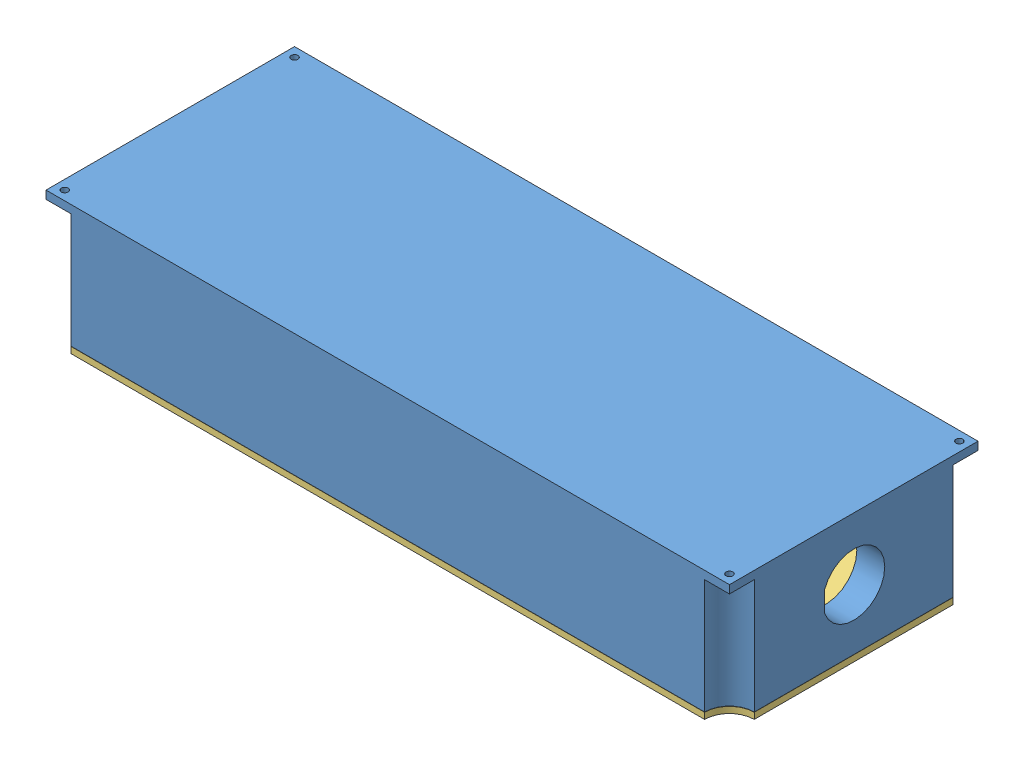
SolidWorks assembly HNOIPackageASSy, configuration Default. Lengths in mm.
Overall size (279.48 52.7 101.7).
3 component instances, 3 part files, 5 mates.
Components (placement in the parent):
- box1-1: box1 [Default] at origin size (279.4 50.8 101.6)
- Pcb,display,rpi-1: Pcb,display,rpi [Default] at (63.0376 143.4996 96.6647) x (-1 0 0) z (0 -1 0) size (203.2 76.2 25.48)
- Lid-1: Lid [Default] at (25.4809 -52.7049 0.1037) x (1 0 0) z (0 0 -1) size (279.4 2.54 101.6)
Mates (geometry in assembly coordinates):
- Coincident1: coincident anti-aligned: plane of box1-1 through (102.87 -17.78 29.21) normal (0 -1 0); plane of Pcb,display,rpi-1 through (-0.2709 -17.78 0.3241) normal (0 1 0)
- Parallel1: parallel anti-aligned: line of box1-1 through (-102.87 -17.78 -39.37) axis (0 0 1); line of Pcb,display,rpi-1 through (101.3291 -19.38 38.4241) axis (0 0 -1)
- Coincident6: coincident: plane of box1-1 through (165.1 -33.782 -50.8) normal (0 -1 0); plane of Lid-1 through (25.4 -33.782 0) normal (0 1 0)
- Coincident8: coincident: circle of box1-1; circle of Lid-1
- Coincident9: coincident: circle of box1-1; circle of Lid-1
